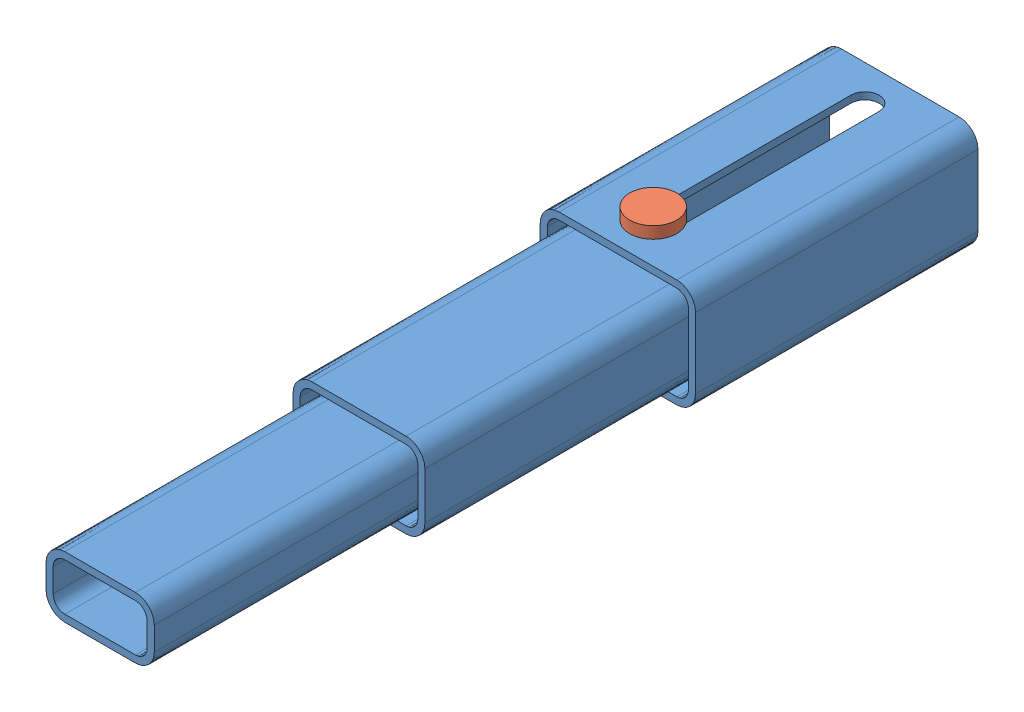
SolidWorks assembly advancedmates, configuration Default. Lengths in mm.
Overall size (66 60 340).
4 component instances, 2 part files, 9 mates.
Components (placement in the parent):
- mechinicalmates-2: mechinicalmates [Large] at (49.9406 64.9365 27.8218) x (1 0 0) z (0 -1 0) size (66 120 46)
- mechinicalmates-3: mechinicalmates [Medium] at (49.9406 64.9365 137.8218) x (1 0 0) z (0 -1 0) size (56 120 36)
- mechinicalmates-4: mechinicalmates [Small] at (49.9406 64.9365 247.8218) x (1 0 0) z (0 -1 0) size (46 120 26)
- pin-1: pin [Default] at (49.9406 64.9365 132.8218) size (20 60 20)
Mates (geometry in assembly coordinates):
- Width1: width anti-aligned: plane of mechinicalmates-2 through (74.9406 84.9365 147.8218) normal (0 -1 0); plane of mechinicalmates-2 through (74.9406 44.9365 147.8218) normal (0 1 0); plane of mechinicalmates-3 through (69.9406 82.9365 257.8218) normal (0 1 0); plane of mechinicalmates-3 through (69.9406 46.9365 257.8218) normal (0 -1 0)
- Width2: width anti-aligned: plane of mechinicalmates-2 through (79.9406 49.9365 147.8218) normal (-1 0 0); plane of mechinicalmates-2 through (19.9406 49.9365 147.8218) normal (1 0 0); plane of mechinicalmates-3 through (77.9406 54.9365 257.8218) normal (1 0 0); plane of mechinicalmates-3 through (21.9406 54.9365 257.8218) normal (-1 0 0)
- Width3: width anti-aligned: plane of mechinicalmates-3 through (69.9406 79.9365 257.8218) normal (0 -1 0); plane of mechinicalmates-3 through (69.9406 49.9365 257.8218) normal (0 1 0); plane of mechinicalmates-4 through (64.9406 77.9365 367.8218) normal (0 1 0); plane of mechinicalmates-4 through (64.9406 51.9365 367.8218) normal (0 -1 0)
- Width4: width anti-aligned: plane of mechinicalmates-4 through (72.9406 59.9365 367.8218) normal (1 0 0); plane of mechinicalmates-4 through (26.9406 59.9365 367.8218) normal (-1 0 0); plane of mechinicalmates-3 through (74.9406 54.9365 257.8218) normal (-1 0 0); plane of mechinicalmates-3 through (24.9406 54.9365 257.8218) normal (1 0 0)
- Linear/Linear Coupler1: linear coupler = 1 : 2 mm: plane of mechinicalmates-3 through (29.9406 74.9365 137.8218) normal (0 0 -1); plane of mechinicalmates-4 through (34.9406 69.9365 247.8218) normal (0 0 -1)
- Width5: width anti-aligned: plane of pin-1 through (49.9406 89.9365 132.8218) normal (0 -1 0); plane of pin-1 through (49.9406 39.9365 132.8218) normal (0 1 0); plane of mechinicalmates-3 through (69.9406 82.9365 257.8218) normal (0 1 0); plane of mechinicalmates-3 through (69.9406 46.9365 257.8218) normal (0 -1 0)
- Coincident6: coincident aligned: plane of mechinicalmates-2 through (49.9406 64.9365 27.8218) normal (1 0 0); plane of pin-1 through (49.9406 64.9365 132.8218) normal (1 0 0)
- Tangent1: tangent anti-aligned: plane of mechinicalmates-3 through (29.9406 74.9365 137.8218) normal (0 0 -1); cylinder of pin-1 through (49.9406 89.9365 132.8218) axis (0 -1 0) radius 5
- Slot4: slot aligned: cylinder of pin-1 through (49.9406 89.9365 132.8218) axis (0 -1 0) radius 5; cylinder of mechinicalmates-2 through (49.9406 87.9365 42.8218) axis (0 -1 0) radius 6; cylinder of mechinicalmates-2 through (49.9406 87.9365 132.8218) axis (0 -1 0) radius 6
